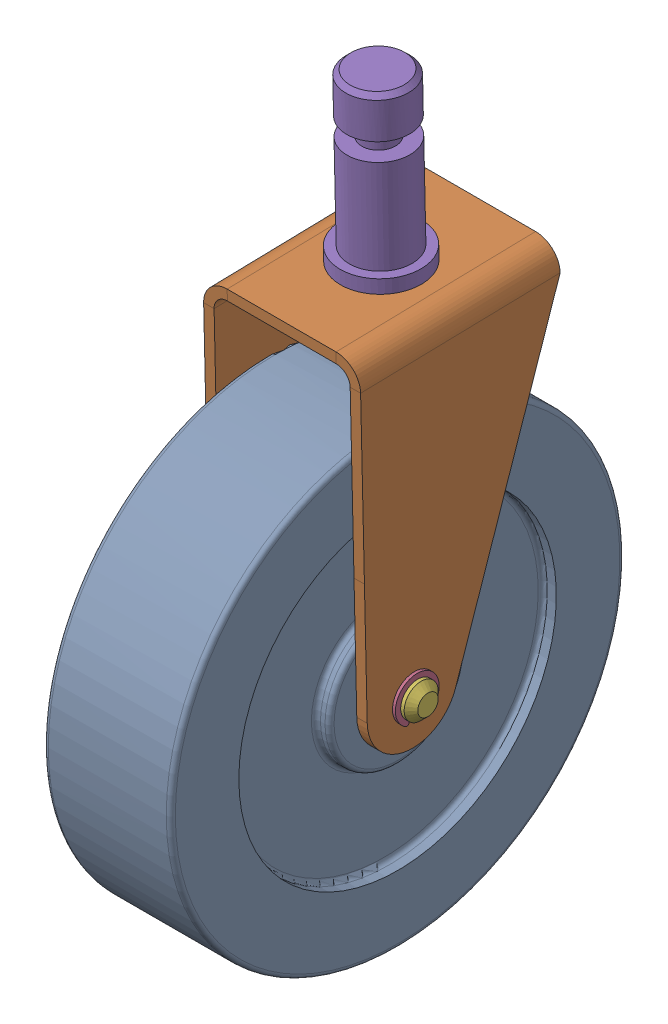
SolidWorks assembly Assem Wheele, configuration Default. Lengths in mm.
Overall size (40 156.51 100).
6 component instances, 6 part files, 11 mates.
Components (placement in the parent):
- Wheel s-1: Wheel s [Default] at (42.518 38.0039 83.6543) size (28 100 100)
- Brackets-1: Brackets [Default] at (42.518 28.7828 49.4348) x (1 0 0) z (0 -0.022835 0.999739) size (34.6 79.05 44)
- Brussh-1: Brussh [Default] at (42.518 38.0039 83.6543) x (0 1 0) z (0 0 1) size (13.95 28 13.95)
- Circlips-1: Circlips [Default] at (60.5355 38.0039 83.6543) x (0 0 -1) z (1 0 0) size (9.65 8.99 0.64)
- Postt-1: Postt [Default] at (42.518 101.3114 73.0971) x (0.999012 -0.001015 0.044435) z (-0.044446 -0.022812 0.998751) size (18 43 18)
- Shafts-1: Shafts [Default] at (23.218 38.0039 83.6543) x (0 0.999739 0.022835) z (0 -0.022835 0.999739) size (16 40 16)
Mates (geometry in assembly coordinates):
- Concentric1: concentric anti-aligned: cylinder of Wheel s-1 through (42.518 38.0039 83.6543) axis (-1 0 0) radius 7; cylinder of Brackets-1 through (17.818 38.0039 83.6543) axis (1 0 0) radius 4
- Width1: width anti-aligned: plane of Wheel s-1 through (56.518 73.0039 83.6543) normal (1 0 0); plane of Brackets-1 through (28.518 88.0039 83.6543) normal (-1 0 0); plane of Wheel s-1 through (25.218 104.5081 95.1759) normal (-1 0 0); plane of Brackets-1 through (59.818 104.5081 95.1759) normal (1 0 0)
- Concentric2: concentric aligned: cylinder of Brackets-1 through (42.518 65.3208 72.2751) axis (0 0.999739 0.022835) radius 7.25; cylinder of Postt-1 through (42.518 144.3002 74.079) axis (0 0.999739 0.022835) radius 7
- Coincident1: coincident anti-aligned: plane of Brackets-1 through (57.518 106.8075 95.2284) normal (0 0.999739 0.022835); plane of Postt-1 through (49.5111 107.3028 73.5452) normal (0 -0.999739 -0.022835)
- Concentric3: concentric anti-aligned: cylinder of Brackets-1 through (17.818 38.0039 83.6543) axis (1 0 0) radius 4; cylinder of Shafts-1 through (63.218 38.0039 83.6543) axis (-1 0 0) radius 3.75
- Parallel1: parallel anti-aligned: plane of Brackets-1 through (38.218 44.0308 82.5416) normal (0 -0.022835 0.999739); plane of Shafts-1 through (43.218 38.0267 82.6546) normal (0 0.022835 -0.999739)
- Coincident3: coincident anti-aligned: plane of Brackets-1 through (25.218 104.5081 95.1759) normal (-1 0 0); plane of Shafts-1 through (25.218 38.0039 83.6543) normal (1 0 0)
- Concentric4: concentric anti-aligned: cylinder of Brussh-1 through (28.518 38.0039 83.6543) axis (1 0 0) radius 4; cylinder of Shafts-1 through (63.218 38.0039 83.6543) axis (-1 0 0) radius 3.75
- Width2: width anti-aligned: plane of Brussh-1 through (28.518 38.0039 83.6543) normal (-1 0 0); plane of Brackets-1 through (56.518 38.0039 83.6543) normal (1 0 0); plane of Brussh-1 through (59.818 104.5081 95.1759) normal (1 0 0); plane of Brackets-1 through (25.218 104.5081 95.1759) normal (-1 0 0)
- Concentric5: concentric anti-aligned: cylinder of Circlips-1 through (60.853 38.0039 83.6543) axis (-1 0 0) radius 2.31; cylinder of Shafts-1 through (63.218 38.0039 83.6543) axis (1 0 0) radius 3.2
- Coincident4: coincident anti-aligned: plane of Circlips-1 through (60.218 38.0039 83.6543) normal (-1 0 0); plane of Shafts-1 through (60.218 38.1226 78.4556) normal (1 0 0)
